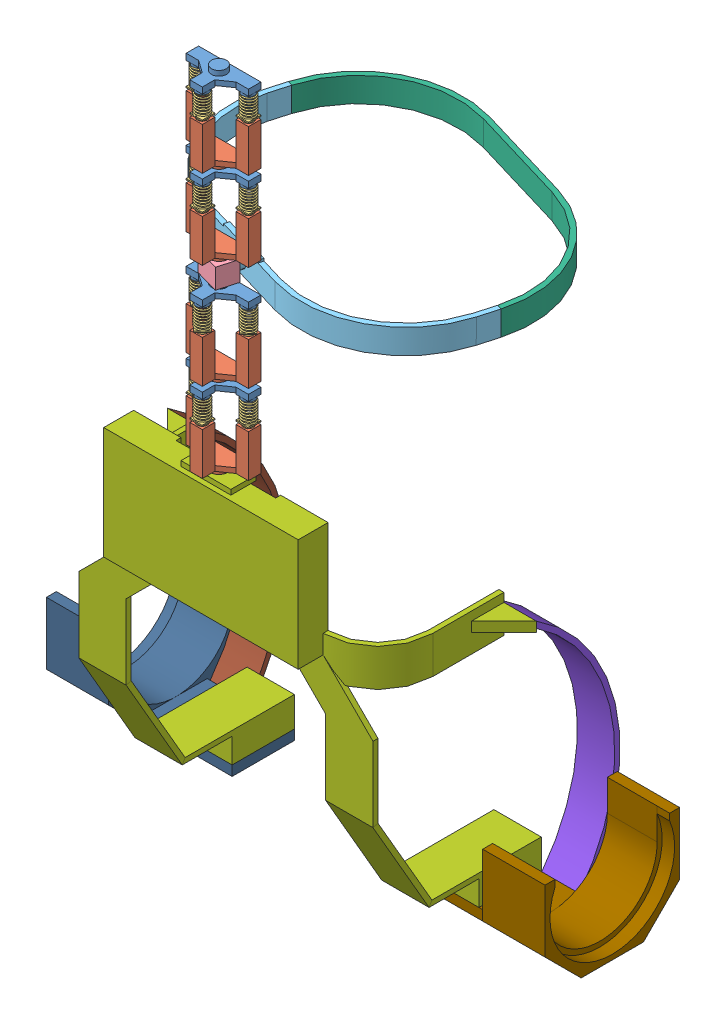
SolidWorks assembly torse_v3, configuration Default. Lengths in mm.
Overall size (400 579.94 248.73).
28 component instances, 11 part files, 73 mates.
Components (placement in the parent):
- unit_p1-1: unit_p1 [Default] at (27.4082 24.1929 24.0012) size (50 11 27)
- unit_p2-1: unit_p2 [Default] at (27.4082 -27.8071 24.0012) x (-1 0 0) z (0 0 1) size (50 38 27)
- unit_pole_b-1: unit_pole_b [Default] at (7.4082 4.1929 24.0012) size (12.02 47.5 12.62)
- unit_pole_b-2: unit_pole_b [Default] at (27.4082 4.1929 41.0012) x (0 0 -1) z (1 0 0) size (12.02 47.5 12.62)
- unit_pole_b-3: unit_pole_b [Default] at (47.4082 4.1929 24.0012) size (12.02 47.5 12.62)
- unit_p1-2: unit_p1 [Default] at (27.4082 -39.8071 24.0012) size (50 11 27)
- unit_p2-2: unit_p2 [Default] at (27.4082 -91.8071 24.0012) x (-1 0 0) z (0 0 1) size (50 38 27)
- unit_pole_b-4: unit_pole_b [Default] at (7.4082 -59.8071 24.0012) x (0.99966 0 -0.026086) z (0.026086 0 0.99966) size (12.02 47.5 12.62)
- unit_pole_b-5: unit_pole_b [Default] at (27.4082 -59.8071 41.0012) size (12.02 47.5 12.62)
- unit_pole_b-6: unit_pole_b [Default] at (47.4082 -59.8071 24.0012) size (12.02 47.5 12.62)
- waist_rotate_v3-1: waist_rotate_v3 [默认] at (27.4082 -107.8071 27.6012) x (-0.961921 0 -0.273328) z (-0.273328 0 0.961921) size (20 24 18)
- waist_back-1: waist_back [Default] at (29.2554 -96.8092 21.8885) x (0.961736 -0.019589 0.273275) z (0.273328 0 -0.961921) size (248 22 104)
- front_a-1: front_a [Default] at (58.756 -97.8091 -82.0043) x (0.961736 -0.019589 0.273275) z (0.273328 0 -0.961921) size (248 20 84)
- unit_p1-3: unit_p1 [Default] at (27.4082 -123.8071 24.0012) size (50 11 27)
- unit_p2-3: unit_p2 [Default] at (27.4082 -175.8071 24.0012) x (-1 0 0) z (0 0 1) size (50 38 27)
- unit_pole_b-7: unit_pole_b [Default] at (7.4082 -143.8071 24.0012) x (0.627764 0 -0.778403) z (0.778403 0 0.627764) size (12.02 47.5 12.62)
- unit_pole_b-8: unit_pole_b [Default] at (47.4082 -143.8071 24.0012) x (-0.721684 0 0.692222) z (-0.692222 0 -0.721684) size (12.02 47.5 12.62)
- unit_pole_b-9: unit_pole_b [Default] at (27.4082 -143.8071 41.0012) x (-0.692241 0 0.721666) z (-0.721666 0 -0.692241) size (12.02 47.5 12.62)
- unit_p1-4: unit_p1 [Default] at (27.4082 -187.8071 24.0012) size (50 11 27)
- unit_p2-4: unit_p2 [Default] at (27.4082 -239.8071 24.0012) x (-1 0 0) z (0 0 1) size (50 38 27)
- unit_pole_b-10: unit_pole_b [Default] at (7.4082 -207.8071 24.0012) x (0.998417 0 -0.056251) z (0.056251 0 0.998417) size (12.02 47.5 12.62)
- unit_pole_b-11: unit_pole_b [Default] at (27.4082 -207.8071 41.0012) x (0.99954 0 0.030344) z (-0.030344 0 0.99954) size (12.02 47.5 12.62)
- unit_pole_b-12: unit_pole_b [Default] at (47.4082 -207.8071 24.0012) x (-0.067406 0 0.997726) z (-0.997726 0 -0.067406) size (12.02 47.5 12.62)
- torso_back-1: torso_back [Default] at (27.4082 -291.8071 18.1012) x (-1 0 0) z (0 0 1) size (296 295.94 155)
- addtion_v0.1-1: addtion_v0.1 [Default] at (175.4082 -486.3955 -78.8988) x (-1 0 0) z (0 0 1) size (30 213.78 67.22)
- torso_shoulder-1: torso_shoulder [默认] at (107.4082 -543.7494 -87.8988) x (0 0 1) z (1 0 0) size (108 79.05 120)
- torso_shoulder_v0.3-1: torso_shoulder_v0.3 [默认] at (-52.5918 -543.7494 -87.8988) x (0 0 -1) z (-1 0 0) size (108 79.05 120)
- addtion_v0.3-1: addtion_v0.3 [Default] at (-90.5918 -486.3955 -78.8988) x (-1 0 0) z (0 0 1) size (30 213.78 67.22)
Mates (geometry in assembly coordinates):
- 同心1: concentric aligned: cylinder of unit_p2-1 through (7.4082 -27.8071 24.0012) axis (0 1 0) radius 4; cylinder of unit_pole_b-1 through (7.4082 -25.8071 24.0012) axis (0 1 0) radius 4
- 同心2: concentric aligned: cylinder of unit_p1-1 through (7.4082 21.1929 24.0012) axis (0 1 0) radius 5; cylinder of unit_pole_b-1 through (7.4082 -25.8071 24.0012) axis (0 1 0) radius 4
- 重合1: coincident anti-aligned: plane of unit_p1-1 through (7.4082 21.1929 24.0012) normal (0 -1 0); plane of unit_pole_b-1 through (7.4082 21.1929 24.0012) normal (0 1 0)
- 同心3: concentric aligned: cylinder of unit_p2-1 through (47.4082 -27.8071 24.0012) axis (0 1 0) radius 4; cylinder of unit_pole_b-3 through (47.4082 -25.8071 24.0012) axis (0 1 0) radius 4
- 重合2: coincident anti-aligned: plane of unit_p1-1 through (47.4082 21.1929 24.0012) normal (0 -1 0); plane of unit_pole_b-3 through (47.4082 21.1929 24.0012) normal (0 1 0)
- 同心4: concentric aligned: cylinder of unit_p2-1 through (27.4082 -27.8071 41.0012) axis (0 1 0) radius 4; cylinder of unit_pole_b-2 through (27.4082 -25.8071 41.0012) axis (0 1 0) radius 4
- 重合3: coincident anti-aligned: plane of unit_p1-1 through (27.4082 21.1929 41.0012) normal (0 -1 0); plane of unit_pole_b-2 through (27.4082 21.1929 41.0012) normal (0 1 0)
- 同心5: concentric aligned: cylinder of unit_p1-1 through (27.4082 21.1929 41.0012) axis (0 1 0) radius 5; cylinder of unit_pole_b-2 through (27.4082 -25.8071 41.0012) axis (0 1 0) radius 4
- 同心6: concentric aligned: cylinder of unit_p1-1 through (47.4082 21.1929 24.0012) axis (0 1 0) radius 5; cylinder of unit_pole_b-3 through (47.4082 -25.8071 24.0012) axis (0 1 0) radius 4
- 同心7: concentric anti-aligned: cylinder of unit_p2-1 through (27.4082 -35.8071 27.6012) axis (0 1 0) radius 7; cylinder of unit_p1-2 through (27.4082 -31.8071 27.6012) axis (0 -1 0) radius 6
- 重合4: coincident anti-aligned: plane of unit_p2-1 through (27.4082 -31.8071 24.0012) normal (0 -1 0); plane of unit_p1-2 through (27.4082 -31.8071 27.6012) normal (0 1 0)
- 同心8: concentric aligned: cylinder of unit_p2-2 through (47.4082 -91.8071 24.0012) axis (0 1 0) radius 4; cylinder of unit_pole_b-6 through (47.4082 -89.8071 24.0012) axis (0 1 0) radius 4
- 同心9: concentric aligned: cylinder of unit_p2-2 through (27.4082 -91.8071 41.0012) axis (0 1 0) radius 4; cylinder of unit_pole_b-5 through (27.4082 -89.8071 41.0012) axis (0 1 0) radius 4
- 同心10: concentric aligned: cylinder of unit_p2-2 through (7.4082 -91.8071 24.0012) axis (0 1 0) radius 4; cylinder of unit_pole_b-4 through (7.4082 -89.8071 24.0012) axis (0 1 0) radius 4
- 同心11: concentric aligned: cylinder of unit_p1-2 through (7.4082 -42.8071 24.0012) axis (0 1 0) radius 5; cylinder of unit_pole_b-4 through (7.4082 -89.8071 24.0012) axis (0 1 0) radius 4
- 同心12: concentric aligned: cylinder of unit_p1-2 through (27.4082 -42.8071 41.0012) axis (0 1 0) radius 5; cylinder of unit_pole_b-5 through (27.4082 -89.8071 41.0012) axis (0 1 0) radius 4
- 同心13: concentric aligned: cylinder of unit_p1-2 through (47.4082 -42.8071 24.0012) axis (0 1 0) radius 5; cylinder of unit_pole_b-6 through (47.4082 -89.8071 24.0012) axis (0 1 0) radius 4
- 距离1: distance = 52 mm anti-aligned: plane of unit_p2-1 through (27.4082 -27.8071 24.0012) normal (0 1 0); plane of unit_p1-1 through (27.4082 24.1929 24.0012) normal (0 -1 0)
- 平行1: parallel aligned: plane of unit_p2-1 through (32.4082 2.1929 36.0012) normal (0 0 -1); plane of unit_pole_b-2 through (32.4082 5.1929 36.0012) normal (0 0 -1)
- 重合5: coincident aligned: plane of unit_p2-1 through (2.4082 -31.8071 19.0012) normal (0 0 -1); plane of unit_pole_b-3 through (42.4082 5.1929 19.0012) normal (0 0 -1)
- 重合6: coincident aligned: plane of unit_p2-1 through (2.4082 -31.8071 19.0012) normal (0 0 -1); plane of unit_pole_b-1 through (2.4082 5.1929 19.0012) normal (0 0 -1)
- 重合7: coincident anti-aligned: plane of unit_p1-2 through (7.4082 -42.8071 24.0012) normal (0 -1 0); plane of unit_pole_b-4 through (7.4082 -42.8071 24.0012) normal (0 1 0)
- 重合8: coincident anti-aligned: plane of unit_p1-2 through (27.4082 -42.8071 41.0012) normal (0 -1 0); plane of unit_pole_b-5 through (27.4082 -42.8071 41.0012) normal (0 1 0)
- 重合9: coincident anti-aligned: plane of unit_p1-2 through (47.4082 -42.8071 24.0012) normal (0 -1 0); plane of unit_pole_b-6 through (47.4082 -42.8071 24.0012) normal (0 1 0)
- 距离2: distance = 52 mm anti-aligned: plane of unit_p1-2 through (27.4082 -39.8071 24.0012) normal (0 -1 0); plane of unit_p2-2 through (27.4082 -91.8071 24.0012) normal (0 1 0)
- 重合11: coincident anti-aligned: plane of waist_rotate_v3-1 through (30.1414 -107.8071 17.982) normal (0.273328 0 -0.961921); plane of waist_back-1 through (30.1414 -107.8071 17.982) normal (-0.273328 0 0.961921)
- 同心15: concentric anti-aligned: cylinder of waist_rotate_v3-1 through (30.1414 -107.8071 17.982) axis (-0.273328 0 0.961921) radius 6; cylinder of waist_back-1 through (30.1414 -107.8071 17.982) axis (0.273328 0 -0.961921) radius 6
- 重合12: coincident anti-aligned: plane of waist_back-1 through (-60.8762 -115.3762 -115.9975) normal (0.273328 0 -0.961921); plane of front_a-1 through (-60.8762 -115.3762 -115.9975) normal (-0.273328 0 0.961921)
- 重合13: coincident aligned: plane of waist_back-1 through (15.9133 -97.0255 -77.5446) normal (0.018843 0.999808 0.005354); plane of front_a-1 through (97.2254 -98.5926 -71.0733) normal (0.018843 0.999808 0.005354)
- 重合14: coincident aligned: line of waist_back-1 through (-60.8762 -115.3762 -115.9975) axis (0.018843 0.999808 0.005354); line of front_a-1 through (-60.8762 -115.3762 -115.9975) axis (0.018843 0.999808 0.005354)
- 同心18: concentric aligned: cylinder of unit_p2-3 through (7.4082 -175.8071 24.0012) axis (0 1 0) radius 4; cylinder of unit_pole_b-7 through (7.4082 -173.8071 24.0012) axis (0 1 0) radius 4
- 同心19: concentric aligned: cylinder of unit_p2-3 through (27.4082 -175.8071 41.0012) axis (0 1 0) radius 4; cylinder of unit_pole_b-9 through (27.4082 -173.8071 41.0012) axis (0 1 0) radius 4
- 同心20: concentric aligned: cylinder of unit_p2-3 through (47.4082 -175.8071 24.0012) axis (0 1 0) radius 4; cylinder of unit_pole_b-8 through (47.4082 -173.8071 24.0012) axis (0 1 0) radius 4
- 重合17: coincident anti-aligned: plane of unit_p1-3 through (47.4082 -126.8071 24.0012) normal (0 -1 0); plane of unit_pole_b-8 through (47.4082 -126.8071 24.0012) normal (0 1 0)
- 重合18: coincident anti-aligned: plane of unit_p1-3 through (47.4082 -126.8071 24.0012) normal (0 -1 0); plane of unit_pole_b-9 through (27.4082 -126.8071 41.0012) normal (0 1 0)
- 同心23: concentric aligned: cylinder of unit_p1-3 through (7.4082 -126.8071 24.0012) axis (0 1 0) radius 5; cylinder of unit_pole_b-7 through (7.4082 -173.8071 24.0012) axis (0 1 0) radius 4
- 同心24: concentric aligned: cylinder of unit_p1-3 through (27.4082 -126.8071 41.0012) axis (0 1 0) radius 5; cylinder of unit_pole_b-9 through (27.4082 -173.8071 41.0012) axis (0 1 0) radius 4
- 重合19: coincident anti-aligned: plane of unit_p1-3 through (7.4082 -126.8071 24.0012) normal (0 -1 0); plane of unit_pole_b-7 through (7.4082 -126.8071 24.0012) normal (0 1 0)
- 距离3: distance = 52 mm anti-aligned: plane of unit_p1-3 through (27.4082 -123.8071 24.0012) normal (0 -1 0); plane of unit_p2-3 through (27.4082 -175.8071 24.0012) normal (0 1 0)
- 同心26: concentric anti-aligned: cylinder of unit_p2-2 through (27.4082 -99.8071 27.6012) axis (0 1 0) radius 7; cylinder of waist_rotate_v3-1 through (27.4082 -95.8071 27.6012) axis (0 -1 0) radius 4
- 重合21: coincident anti-aligned: plane of unit_p2-2 through (27.4082 -95.8071 24.0012) normal (0 -1 0); plane of waist_rotate_v3-1 through (27.4082 -95.8071 27.6012) normal (0 1 0)
- 同心27: concentric anti-aligned: cylinder of waist_rotate_v3-1 through (27.4082 -119.8071 27.6012) axis (0 1 0) radius 3; cylinder of unit_p1-3 through (27.4082 -115.8071 27.6012) axis (0 -1 0) radius 6
- 重合22: coincident anti-aligned: plane of waist_rotate_v3-1 through (27.4082 -119.8071 27.6012) normal (0 -1 0); plane of unit_p1-3 through (27.4082 -119.8071 24.0012) normal (0 1 0)
- 平行2: parallel aligned: plane of unit_p2-2 through (2.4082 -95.8071 19.0012) normal (0 0 -1); plane of unit_p1-3 through (52.4082 -119.8071 19.0012) normal (0 0 -1)
- 同心28: concentric anti-aligned: cylinder of unit_p2-3 through (27.4082 -183.8071 27.6012) axis (0 1 0) radius 7; cylinder of unit_p1-4 through (27.4082 -179.8071 27.6012) axis (0 -1 0) radius 6
- 重合23: coincident anti-aligned: plane of unit_p2-3 through (27.4082 -179.8071 24.0012) normal (0 -1 0); plane of unit_p1-4 through (27.4082 -179.8071 27.6012) normal (0 1 0)
- 同心29: concentric aligned: cylinder of unit_p2-4 through (7.4082 -239.8071 24.0012) axis (0 1 0) radius 4; cylinder of unit_pole_b-10 through (7.4082 -237.8071 24.0012) axis (0 1 0) radius 4
- 同心30: concentric aligned: cylinder of unit_p2-4 through (27.4082 -239.8071 41.0012) axis (0 1 0) radius 4; cylinder of unit_pole_b-11 through (27.4082 -237.8071 41.0012) axis (0 1 0) radius 4
- 同心31: concentric aligned: cylinder of unit_p2-4 through (47.4082 -239.8071 24.0012) axis (0 1 0) radius 4; cylinder of unit_pole_b-12 through (47.4082 -237.8071 24.0012) axis (0 1 0) radius 4
- 同心32: concentric aligned: cylinder of unit_p1-4 through (47.4082 -190.8071 24.0012) axis (0 1 0) radius 5; cylinder of unit_pole_b-12 through (47.4082 -237.8071 24.0012) axis (0 1 0) radius 4
- 同心33: concentric aligned: cylinder of unit_p1-4 through (27.4082 -190.8071 41.0012) axis (0 1 0) radius 5; cylinder of unit_pole_b-11 through (27.4082 -237.8071 41.0012) axis (0 1 0) radius 4
- 同心34: concentric aligned: cylinder of unit_p1-4 through (7.4082 -190.8071 24.0012) axis (0 1 0) radius 5; cylinder of unit_pole_b-10 through (7.4082 -237.8071 24.0012) axis (0 1 0) radius 4
- 重合24: coincident anti-aligned: plane of unit_p1-4 through (7.4082 -190.8071 24.0012) normal (0 -1 0); plane of unit_pole_b-10 through (7.4082 -190.8071 24.0012) normal (0 1 0)
- 重合25: coincident anti-aligned: plane of unit_p1-4 through (27.4082 -190.8071 41.0012) normal (0 -1 0); plane of unit_pole_b-11 through (27.4082 -190.8071 41.0012) normal (0 1 0)
- 重合26: coincident anti-aligned: plane of unit_p1-4 through (47.4082 -190.8071 24.0012) normal (0 -1 0); plane of unit_pole_b-12 through (47.4082 -190.8071 24.0012) normal (0 1 0)
- 距离4: distance = 52 mm anti-aligned: plane of unit_p1-4 through (27.4082 -187.8071 24.0012) normal (0 -1 0); plane of unit_p2-4 through (27.4082 -239.8071 24.0012) normal (0 1 0)
- 平行3: parallel aligned: plane of unit_p2-3 through (2.4082 -179.8071 19.0012) normal (0 0 -1); plane of unit_p2-4 through (2.4082 -243.8071 19.0012) normal (0 0 -1)
- 同心35: concentric anti-aligned: cylinder of unit_p2-4 through (27.4082 -247.8071 27.6012) axis (0 1 0) radius 7; cylinder of torso_back-1 through (27.4082 -243.8071 27.6012) axis (0 -1 0) radius 6
- 重合27: coincident anti-aligned: plane of unit_p2-4 through (27.4082 -243.8071 24.0012) normal (0 -1 0); plane of torso_back-1 through (27.4082 -243.8071 27.6012) normal (0 1 0)
- 平行4: parallel aligned: plane of unit_p2-4 through (2.4082 -243.8071 19.0012) normal (0 0 -1); plane of torso_back-1 through (27.4082 -291.8071 18.1012) normal (0 0 -1)
- 重合28: coincident anti-aligned: plane of torso_back-1 through (27.4082 -539.7494 18.1012) normal (0 -1 0); plane of torso_shoulder-1 through (107.4082 -539.7494 -112.8988) normal (0 1 0)
- 重合29: coincident aligned: plane of torso_back-1 through (107.4082 -515.7494 -22.8988) normal (-1 0 0); plane of torso_shoulder-1 through (107.4082 -543.7494 -87.8988) normal (-1 0 0)
- 重合30: coincident aligned: plane of torso_back-1 through (145.4082 -539.7494 -62.8988) normal (0 0 1); plane of torso_shoulder-1 through (107.4082 -547.7494 -62.8988) normal (0 0 1)
- 平行5: parallel aligned: plane of unit_p2-1 through (2.4082 -31.8071 19.0012) normal (0 0 -1); plane of unit_p2-2 through (2.4082 -95.8071 19.0012) normal (0 0 -1)
- 重合34: coincident anti-aligned: plane of torso_back-1 through (149.4082 -356.8071 -78.8988) normal (0 0 -1); plane of addtion_v0.1-1 through (145.4082 -338.8298 -78.8988) normal (0 0 1)
- 重合35: coincident: line of torso_back-1 through (175.4082 -333.8071 -78.8988) axis (0 -1 0); plane of addtion_v0.1-1 through (175.4082 -455.6056 -2.1719) normal (1 0 0)
- 重合36: coincident aligned: line of torso_back-1 through (149.4082 -333.8071 -78.8988) axis (1 0 0); line of addtion_v0.1-1 through (145.4082 -333.8071 -78.8988) axis (1 0 0)
- 重合37: coincident: plane of torso_back-1 through (27.4082 -539.7494 18.1012) normal (0 -1 0); plane of torso_shoulder_v0.3-1 through (-52.5918 -539.7494 -62.8988) normal (0 1 0)
- 重合38: coincident: plane of torso_back-1 through (27.4082 -515.7494 -112.8988) normal (0 0 -1); plane of torso_shoulder_v0.3-1 through (-52.5918 -547.7494 -112.8988) normal (0 0 -1)
- 重合39: coincident aligned: plane of torso_back-1 through (-52.5918 -515.7494 -22.8988) normal (1 0 0); plane of torso_shoulder_v0.3-1 through (-52.5918 -543.7494 -87.8988) normal (1 0 0)
- 重合40: coincident: plane of torso_back-1 through (-94.5918 -356.8071 -78.8988) normal (0 0 -1); plane of addtion_v0.3-1 through (-120.5918 -342.8176 -78.8988) normal (0 0 1)
- 重合41: coincident: line of torso_back-1 through (-120.5918 -333.8071 -78.8988) axis (0 -1 0); line of addtion_v0.3-1 through (-120.5918 -342.8176 -78.8988) axis (0 1 0)
- 重合42: coincident aligned: line of torso_back-1 through (-120.5918 -333.8071 -78.8988) axis (1 0 0); line of addtion_v0.3-1 through (-120.5918 -337.795 -78.8988) axis (1 0 0)
